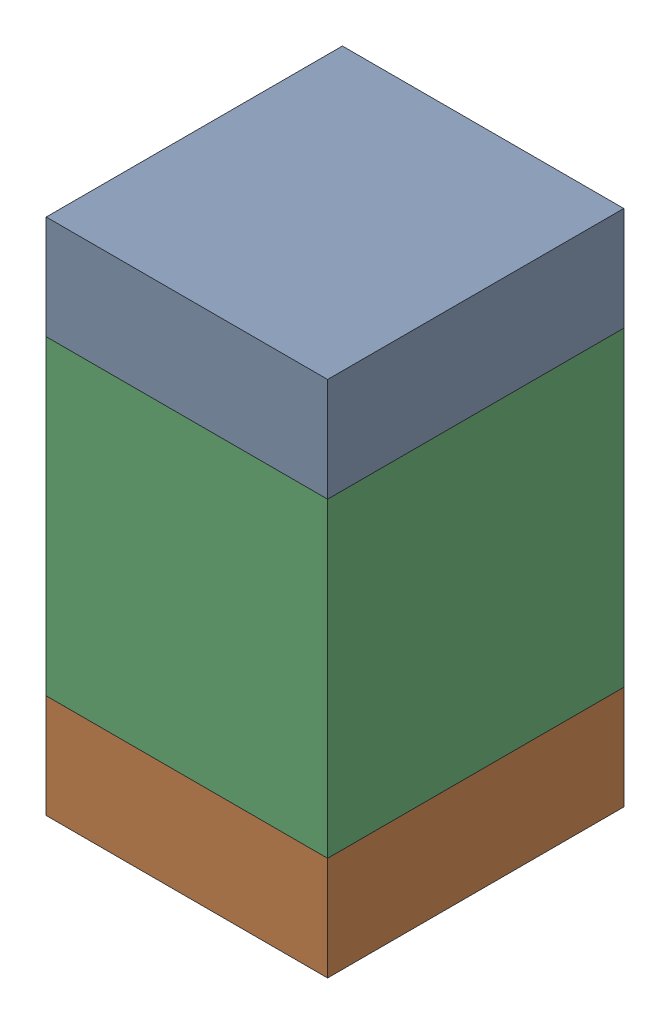
SolidWorks assembly C10, configuration Default. Lengths in mm.
Overall size (0.95 1.75 1).
6 component instances, 2 part files, 0 mates.
Components (placement in the parent):
- 959208664-1: 959208664 [Default] at (109.7632 77.5843 0) size (0.95 0.35 1)
  - Extruded-14-1: Extruded-14 [Default] at origin size (0.95 0.35 1)
- 959208664-2: 959208664 [Default] at (109.7632 76.1843 0) size (0.95 0.35 1)
  - Extruded-14-1: Extruded-14 [Default] at origin size (0.95 0.35 1)
- 959208528-1: 959208528 [Default] at (109.7632 76.8843 0) size (0.95 1.05 1)
  - Extruded-15-1: Extruded-15 [Default] at origin size (0.95 1.05 1)
